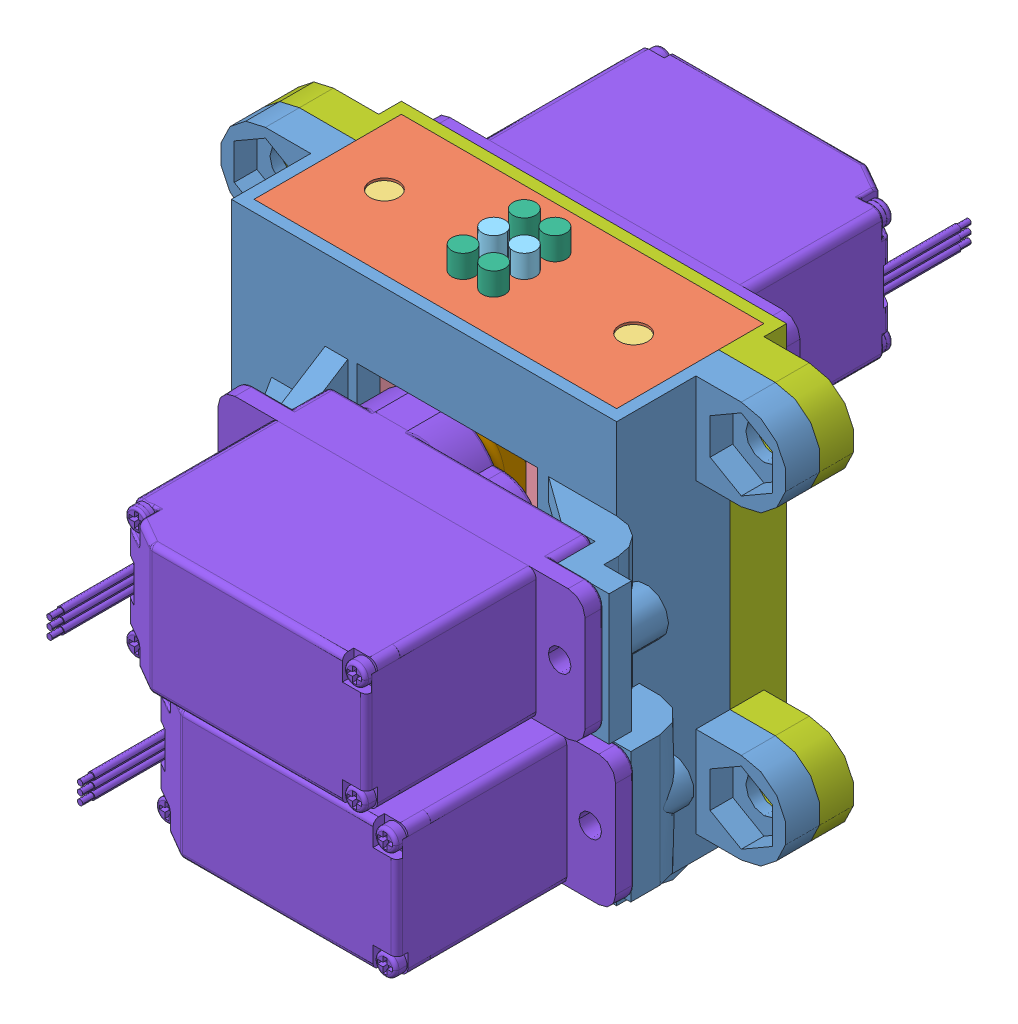
SolidWorks assembly Assemblage1, configuration Défaut. Lengths in mm.
Overall size (50 42 70.8).
18 component instances, 9 part files, 44 mates.
Components (placement in the parent):
- bati part 1-1: bati part 1 [Défaut] at (-49.0706 -11.5721 7.5) size (50 40 21.29)
- plaque de guidage-1: plaque de guidage [Défaut] at (-48.0706 25.4279 -6.5) x (1 0 0) z (0 -1 0) size (32 13 3)
- colone de guidage (+fixation)-1: colone de guidage (+fixation) [Défaut] at (-43.697 22.4279 1.3629) x (0.417627 0 -0.908618) z (0.908618 0 0.417627) size (6 39.8 6)
- colone de guidage (+fixation)-2: colone de guidage (+fixation) [Défaut] at (-21.8781 22.4279 1.2641) x (0.538353 0 -0.842719) z (0.842719 0 0.538353) size (6 39.8 6)
- Plaque Rappel Ressort-1: Plaque Rappel Ressort [Défaut] at (-32.0706 17.9279 0) x (0 0 1) z (0 -1 0) size (11 30 16)
- Poinçon Long-1: Poinçon Long [Défaut] at (-32.0706 20.9279 0) x (0 0 1) z (0 -1 0) size (2.6 3.3 25)
- Poinçon Long-2: Poinçon Long [Défaut] at (-32.0706 20.9279 0) x (0 0 -1) z (0 -1 0) size (2.6 3.3 25)
- Poinçon Court-1: Poinçon Court [Défaut] at (-32.0706 21.9279 0) x (0 0 -1) z (0 -1 0) size (2.6 3.3 11)
- Poinçon Court-2: Poinçon Court [Défaut] at (-32.0706 21.9279 -5.4) x (0 0 1) z (0 -1 0) size (2.6 3.3 11)
- Poinçon Court-3: Poinçon Court [Défaut] at (-32.0706 21.9279 5.4) x (0 0 -1) z (0 -1 0) size (2.6 3.3 11)
- Poinçon Court-4: Poinçon Court [Défaut] at (-32.0706 21.9279 0) x (0 0 1) z (0 -1 0) size (2.6 3.3 11)
- bati part 2-1: bati part 2 [Défaut] at (-15.0706 -9.5721 -7.5) x (-1 0 0) z (0 1 0) size (50 11.29 35)
- BON SERVO-1: BON SERVO [Défaut] at (-49.8958 18.419 -27.4) x (0 -1 0) z (-1 0 0) size (11.57 32.01 32.4)
- BON SERVO-2: BON SERVO [Défaut] at (-14.2454 18.419 27.4) x (0 -1 0) z (1 0 0) size (11.57 32.01 32.4)
- BON SERVO-3: BON SERVO [Défaut] at (-14.2454 4.419 24.7) x (0 -1 0) z (1 0 0) size (11.57 32.01 32.4)
- Rotor Servo-1: Rotor Servo [Défaut] at (-31.9216 6.504 -5.6) x (-0.017914 0.99984 0) z (0 0 1) size (7 12 4.5)
- Rotor Servo-2: Rotor Servo [Défaut] at (-31.7263 18.691 5.6) x (-0.062946 -0.998017 0) z (0 0 -1) size (7 12 4.5)
- Rotor Servo-3: Rotor Servo [Défaut] at (-31.9709 -7.4966 -8.3) x (-0.009842 0.999952 0) z (0 0 1) size (7 12 4.5)
Mates (geometry in assembly coordinates):
- Coïncidente1: coincident anti-aligned: plane of bati part 1-1 through (-49.0706 22.4279 7.5) normal (0 1 0); plane of plaque de guidage-1 through (-48.0706 22.4279 -6.5) normal (0 -1 0)
- Coïncidente2: coincident anti-aligned: plane of bati part 1-1 through (-16.0706 22.4279 6.5) normal (-1 0 0); plane of plaque de guidage-1 through (-16.0706 22.4279 -6.5) normal (1 0 0)
- Coïncidente3: coincident anti-aligned: plane of bati part 1-1 through (-48.0706 22.4279 6.5) normal (0 0 -1); plane of plaque de guidage-1 through (-48.0706 22.4279 6.5) normal (0 0 1)
- Coaxiale5: concentric anti-aligned: cylinder of colone de guidage (+fixation)-2 through (-21.0706 -14.5721 0) axis (0 -1 0) radius 2; cylinder of Plaque Rappel Ressort-1 through (-21.0706 4.4279 0) axis (0 1 0) radius 2.1
- Coaxiale6: concentric anti-aligned: cylinder of colone de guidage (+fixation)-1 through (-43.0706 -14.5721 0) axis (0 -1 0) radius 2; cylinder of Plaque Rappel Ressort-1 through (-43.0706 4.4279 0) axis (0 1 0) radius 2.1
- Distance2: distance = 2 mm anti-aligned: plane of Plaque Rappel Ressort-1 through (-32.0706 20.4279 0) normal (0 1 0); plane of plaque de guidage-1 through (-48.0706 22.4279 -6.5) normal (0 -1 0)
- Coaxiale7: concentric anti-aligned: cylinder of plaque de guidage-1 through (-33.4206 22.4279 -2.7) axis (0 1 0) radius 1; cylinder of Poinçon Court-2 through (-33.4206 36.7564 -2.7) axis (0 -1 0) radius 1
- Coaxiale8: concentric anti-aligned: cylinder of plaque de guidage-1 through (-30.7206 22.4279 -2.7) axis (0 1 0) radius 1; cylinder of Poinçon Court-1 through (-30.7206 36.7564 -2.7) axis (0 -1 0) radius 1
- Coaxiale9: concentric anti-aligned: cylinder of plaque de guidage-1 through (-30.7206 22.4279 2.7) axis (0 1 0) radius 1; cylinder of Poinçon Court-3 through (-30.7206 36.7564 2.7) axis (0 -1 0) radius 1
- Coïncidente9: coincident aligned: circle of plaque de guidage-1; cylinder of Poinçon Court-4 through (-33.4206 36.7564 2.7) axis (0 -1 0) radius 1
- Coaxiale10: concentric anti-aligned: cylinder of plaque de guidage-1 through (-33.4206 22.4279 0) axis (0 1 0) radius 1; cylinder of Poinçon Long-1 through (-33.4206 34.7564 0) axis (0 -1 0) radius 1
- Coaxiale11: concentric anti-aligned: cylinder of plaque de guidage-1 through (-30.7206 22.4279 0) axis (0 1 0) radius 1; cylinder of Poinçon Long-2 through (-30.7206 34.7564 0) axis (0 -1 0) radius 1
- Parallèle1: parallel aligned: plane of Plaque Rappel Ressort-1 through (-47.0706 20.4279 -5.5) normal (0 0 -1); plane of Poinçon Long-2 through (-29.2007 31.9279 -1.3) normal (0 0 -1)
- Parallèle2: parallel aligned: plane of Plaque Rappel Ressort-1 through (-47.0706 20.4279 -5.5) normal (0 0 -1); plane of Poinçon Long-1 through (-34.9404 31.9279 -1.3) normal (0 0 -1)
- Coïncidente12: coincident anti-aligned: plane of Plaque Rappel Ressort-1 through (-47.0706 4.4279 38.6059) normal (0 -1 0); plane of Poinçon Long-2 through (-30.7206 4.4279 0) normal (0 1 0)
- Coïncidente13: coincident anti-aligned: plane of Plaque Rappel Ressort-1 through (-47.0706 4.4279 38.6059) normal (0 -1 0); plane of Poinçon Long-1 through (-33.4206 4.4279 0) normal (0 1 0)
- Parallèle3: parallel aligned: plane of Plaque Rappel Ressort-1 through (-47.0706 20.4279 -5.5) normal (0 0 -1); plane of Poinçon Court-2 through (-34.9404 32.9279 -4) normal (0 0 -1)
- Parallèle4: parallel aligned: plane of Plaque Rappel Ressort-1 through (-47.0706 20.4279 -5.5) normal (0 0 -1); plane of Poinçon Court-1 through (-32.0206 32.9279 -4) normal (0 0 -1)
- Parallèle5: parallel aligned: plane of Plaque Rappel Ressort-1 through (-47.0706 20.4279 -5.5) normal (0 0 -1); plane of Poinçon Court-4 through (-34.9404 32.9279 1.4) normal (0 0 -1)
- Parallèle6: parallel aligned: plane of Plaque Rappel Ressort-1 through (-47.0706 20.4279 -5.5) normal (0 0 -1); plane of Poinçon Court-3 through (-32.0206 32.9279 1.4) normal (0 0 -1)
- Coïncidente19: coincident anti-aligned: plane of Plaque Rappel Ressort-1 through (-32.0706 18.4279 0) normal (0 -1 0); plane of Poinçon Court-2 through (-33.4206 18.4279 -2.7) normal (0 1 0)
- Coïncidente20: coincident anti-aligned: plane of Plaque Rappel Ressort-1 through (-32.0706 18.4279 0) normal (0 -1 0); plane of Poinçon Court-1 through (-30.7206 18.4279 -2.7) normal (0 1 0)
- Coïncidente21: coincident anti-aligned: plane of Plaque Rappel Ressort-1 through (-32.0706 18.4279 0) normal (0 -1 0); plane of Poinçon Court-4 through (-33.4206 18.4279 2.7) normal (0 1 0)
- Coïncidente22: coincident aligned: plane of Plaque Rappel Ressort-1 through (-32.0706 18.4279 0) normal (0 -1 0); circle of Poinçon Court-3
- Coïncidente23: coincident anti-aligned: plane of plaque de guidage-1 through (-48.0706 22.4279 -6.5) normal (0 0 -1); plane of bati part 2-1 through (-16.0706 22.4279 -6.5) normal (0 0 1)
- Coïncidente24: coincident aligned: plane of bati part 1-1 through (-49.0706 25.4279 7.5) normal (0 1 0); plane of bati part 2-1 through (-15.0706 25.4279 -7.5) normal (0 1 0)
- Coïncidente25: coincident anti-aligned: plane of plaque de guidage-1 through (-48.0706 22.4279 -6.5) normal (-1 0 0); plane of bati part 2-1 through (-48.0706 22.4279 -6.5) normal (1 0 0)
- Coïncidente26: coincident anti-aligned: plane of bati part 1-1 through (-39.0706 4.4279 7.5) normal (0 -1 0); plane of BON SERVO-3 through (-42.3509 4.4279 13.7) normal (0 1 0)
- Distance3: distance = 0.8 mm aligned: plane of BON SERVO-3 through (-14.2706 3.737 -13.4217) normal (1 0 0); plane of bati part 1-1 through (-15.0706 -9.5721 7.5) normal (1 0 0)
- Coïncidente31: coincident anti-aligned: plane of bati part 1-1 through (-25.0706 18.4279 7.5) normal (0 -1 0); plane of BON SERVO-2 through (-37.0337 18.4279 -10.7217) normal (0 1 0)
- Distance5: distance = 0.8 mm aligned: plane of BON SERVO-2 through (-14.2706 17.737 -10.7217) normal (1 0 0); plane of bati part 1-1 through (-15.0706 -9.5721 7.5) normal (1 0 0)
- Coaxiale12: concentric anti-aligned: circle of BON SERVO-3; cylinder of Rotor Servo-3 through (-32.0309 -1.3969 0.7) axis (0 0 1) radius 1.75
- Distance6: distance = 0.5 mm anti-aligned: plane of BON SERVO-3 through (-32.0309 -1.3969 3.7) normal (0 0 -1); plane of Rotor Servo-3 through (-32.0309 -1.3969 3.2) normal (0 0 1)
- Coaxiale13: concentric anti-aligned: circle of BON SERVO-2; cylinder of Rotor Servo-1 through (-32.0309 12.6031 3.4) axis (0 0 1) radius 1.75
- Distance7: distance = 0.5 mm anti-aligned: plane of Rotor Servo-1 through (-32.0309 12.6031 5.9) normal (0 0 1); plane of BON SERVO-2 through (-32.0309 12.6031 6.4) normal (0 0 -1)
- Coïncidente37: coincident aligned: plane of Poinçon Court-3 through (-32.0206 32.9279 1.4) normal (0 0 -1); plane of Rotor Servo-1 through (-33.2807 12.5807 1.4) normal (0 0 -1)
- Coïncidente38: coincident aligned: plane of Poinçon Long-2 through (-29.2007 31.9279 -1.3) normal (0 0 -1); plane of Rotor Servo-3 through (-33.2808 -1.4092 -1.3) normal (0 0 -1)
- Coaxiale14: concentric anti-aligned: circle of BON SERVO-1; cylinder of Rotor Servo-2 through (-32.1102 12.6031 -3.4) axis (0 0 -1) radius 1.75
- Distance8: distance = 0.5 mm anti-aligned: plane of BON SERVO-1 through (-32.1102 12.6031 -6.4) normal (0 0 1); plane of Rotor Servo-2 through (-32.1102 12.6031 -5.9) normal (0 0 -1)
- Coïncidente40: coincident anti-aligned: plane of bati part 2-1 through (-25.0706 18.4279 -7.5) normal (0 -1 0); plane of BON SERVO-1 through (-21.7902 18.4279 -16.4) normal (0 1 0)
- Distance9: distance = 0.8 mm aligned: plane of BON SERVO-1 through (-49.8706 17.737 10.7217) normal (-1 0 0); plane of bati part 2-1 through (-49.0706 25.4279 -7.5) normal (-1 0 0)
- Coïncidente42: coincident aligned: plane of Poinçon Court-2 through (-32.1206 32.9279 -1.4) normal (0 0 1); plane of Rotor Servo-2 through (-33.3578 12.6817 -1.4) normal (0 0 1)
- Coaxiale15: concentric anti-aligned: cylinder of bati part 1-1 through (-21.0706 -11.5721 0) axis (0 1 0) radius 1.5; cylinder of colone de guidage (+fixation)-2 through (-21.0706 -14.5721 0) axis (0 -1 0) radius 3
- Coïncidente43: coincident anti-aligned: plane of bati part 1-1 through (-49.0706 -9.5721 7.5) normal (0 1 0); plane of colone de guidage (+fixation)-2 through (-22.6856 -9.5721 2.5282) normal (0 -1 0)
